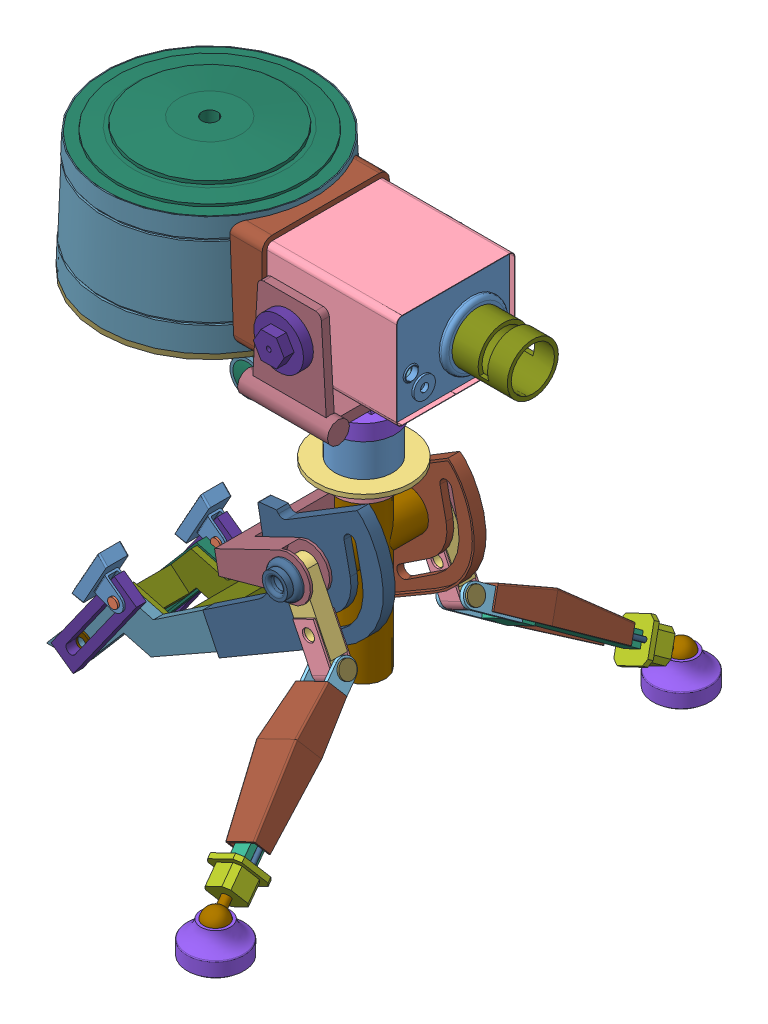
SolidWorks assembly Assem1, configuration AltPosition_Default_1. Lengths in mm.
Overall size (454.66 500.28 528.56).
105 component instances, 64 part files, 136 mates.
Components (placement in the parent):
- center piece assem-2: center piece assem [Default] at (139.2172 608.1262 859.4776) size (134.25 257.4 123.94)
  - center support top section-1: center support top section [Default] at (96.2621 126.254 0) size (58.48 40 58.48)
  - steppo motor-1: steppo motor [Default] at (96.2621 88.254 0) x (0.379391 0 -0.925236) z (-0.925236 0 -0.379391) size (42.44 58.07 42.44)
  - center piece circle wide central ring-1: center piece circle wide central ring [Default] at (96.2621 83.914 0) x (-0.379391 0 0.925236) z (-0.925236 0 -0.379391) size (95 4.34 95)
  - center piece gear support-1: center piece gear support [Default] at (96.2621 51.914 0) x (-0.695714 0 -0.718319) z (0.718319 0 -0.695714) size (55.78 28 55.78)
  - steppo motor screw-1: steppo motor screw [Default] at (87.7742 83.914 -20.287) x (0.961179 0 0.275927) z (0.275927 0 -0.961179) size (5.5 7.62 5.5)
  - steppo motor screw-2: steppo motor screw [Default] at (75.9752 83.914 8.4879) x (0.275927 0 -0.961179) z (-0.961179 0 -0.275927) size (5.5 7.62 5.5)
  - steppo motor screw-3: steppo motor screw [Default] at (104.75 83.914 20.287) x (-0.961179 0 -0.275927) z (-0.275927 0 0.961179) size (5.5 7.62 5.5)
  - steppo motor screw-4: steppo motor screw [Default] at (116.5491 83.914 -8.4879) x (-0.275927 0 0.961179) z (0.961179 0 0.275927) size (5.5 7.62 5.5)
  - center support ball bearign brace-1: center support ball bearign brace [Default] at (96.2621 83.914 0) x (-0.925236 0 -0.379391) z (0.379391 0 -0.925236) size (55.78 10 55.78)
  - center support ball bearign brace top-1: center support ball bearign brace top [Default] at (96.2621 74.914 0) x (-0.922511 0 0.385971) z (-0.385971 0 -0.922511) size (55.78 12 55.78)
  - center piece top hing part-1: center piece top hing part [Default] at (96.2621 123.254 0) x (-1 0 0) z (0 0 -1) size (104.29 49.7 64.01)
  - center support v2-2: center support v2 [Default] at (96.2621 -96.7337 0) size (42.4 158.65 100)
- main side parts-1: main side parts [Default] at (235.4793 627.5876 911.4776) x (0.999891 -0.014742 0) z (0 0 1)
- Mirrormain side parts-2: Mirrormain side parts [Default] at (235.4793 627.5876 807.4776) x (0.999891 -0.014742 0) z (0 0 1)
- wahser spacer-1: wahser spacer [Default] at (235.4793 627.5876 911.4776)
- back handle-1: back handle [Default] at (235.4793 627.5876 924.4776) x (0.986694 0.162587 0) z (0 0 1)
- wahser spacer-2: wahser spacer [Default] at (235.4793 627.5876 935.4776)
- back support-1: back support [Default] at (67.5941 491.4866 904.4776) x (0.999998 0.001848 0) z (0 0 1)
- Mirrorback support-2: Mirrorback support [Default] at (67.5941 491.4866 814.4776) x (0.999998 0.001848 0) z (0 0 1)
- back support backet-1: back support backet [Default] at (28.0399 490.9679 898.4776) x (0.996815 -0.079745 0) z (0 0 1)
- wahser spacer-3: wahser spacer [Default] at (235.4793 627.5876 781.4776)
- wahser spacer-4: wahser spacer [Default] at (235.4793 627.5876 805.4776)
- back foot support bracket-1: back foot support bracket [Default] at (-1.4852 415.687 906.4776) x (0.578557 0.815642 0) z (0 0 1)
- wahser spacer large-1: wahser spacer large [Default] at (-3.7947 436.2499 904.4776) x (0.999256 0.03856 0) z (0 0 1)
- back foot bracket-1: back foot bracket [Default] at (42.2808 501.2065 916.4776) x (-0.48679 -0.873519 0) z (0 0 1)
- back leg pin-1: back leg pin [Default] at (42.2808 501.2065 911.4776)
- back foot support bracket-2: back foot support bracket [Default] at (-1.4852 415.687 802.4776) x (0.578557 0.815642 0) z (0 0 1)
- back foot bracket-2: back foot bracket [Default] at (42.2808 501.2065 812.4776) x (-0.48679 -0.873519 0) z (0 0 1)
- back leg pin-2: back leg pin [Default] at (42.2808 501.2065 807.4776)
- front leg join support-1: front leg join support [Default] at (235.4793 627.5876 915.9776) x (0.900351 0.435164 0) z (0 0 1)
- front leg metal join bracket-1: front leg metal join bracket [Default] at (262.8485 570.5138 924.4776) x (0.900351 0.435164 0) z (0 0 1)
- front leg top half support-1: front leg top half support [Default] at (279.0143 563.4937 924.4776) x (0.900351 0.435164 0) z (-0.355474 0.735472 0.576818)
- front leg top half support-2: front leg top half support [Default] at (258.3063 553.485 924.4776) x (-0.900351 -0.435164 0) z (0.355474 -0.735472 -0.576818)
- front leg midsection suport-1: front leg midsection suport [Default] at (283.5066 527.7725 954.5891) x (0.900351 0.435164 0) z (-0.355474 0.735472 0.576818)
- front leg base support-1: front leg base support [Default] at (311.0558 470.7734 1062.4468) x (0.900351 0.435164 0) z (-0.355474 0.735472 0.576818)
- front foot-1: front foot [Default] at (321.1259 417.8022 1095.0242) x (0.999998 0.001848 0) z (0 0 1)
- front leg ball and socket jont-1: front leg ball and socket jont [Default] at (321.0663 450.0619 1095.0242) x (0.647947 0.717091 0.256798) z (-0.719137 0.464831 0.516502)
- front leg metal join bracket-2: front leg metal join bracket [Default] at (262.8485 570.5138 794.4776) x (0.900351 0.435164 0) z (0 0 1)
- front leg top half support-3: front leg top half support [Default] at (282.6157 565.2344 794.4776) x (-0.900351 -0.435164 0) z (-0.355474 0.735472 -0.576818)
- front leg midsection suport-2: front leg midsection suport [Default] at (276.0416 543.2174 752.253) x (0.900351 0.435164 0) z (0.355474 -0.735472 0.576818)
- front leg base support-2: front leg base support [Default] at (311.0558 470.7734 656.5085) x (0.900351 0.435164 0) z (0.355474 -0.735472 0.576818)
- front leg ball and socket jont-2: front leg ball and socket jont [Default] at (321.0663 450.0619 623.9311) x (0.647947 0.717091 -0.256798) z (0.719137 -0.464831 0.516502)
- front foot-2: front foot [Default] at (321.1259 417.8022 623.9311) x (0.999998 0.001848 0) z (0 0 1)
- front leg join support-3: front leg join support [Default] at (235.4793 627.5876 785.9776) x (0.900351 0.435164 0) z (0 0 1)
- front leg top half support-4: front leg top half support [Default] at (254.7049 551.7443 794.4776) x (0.900351 0.435164 0) z (0.355474 -0.735472 0.576818)
- front foot ligament support-1: front foot ligament support [Default] at (294.5017 533.0242 972.8721) x (-0.960289 -0.027406 0.277656) z (-0.12181 -0.854129 -0.505595)
- front foot ligament support-2: front foot ligament support [Default] at (272.5605 522.4194 972.8721) x (0.748627 0.639123 0.176292) z (-0.613638 0.567282 0.549218)
- front leg metal shroud-1: front leg metal shroud [Default] at (284.766 525.1668 982.9969) x (0.900351 0.435164 0) z (-0.355474 0.735472 0.576818)
- front leg metal shroud-2: front leg metal shroud [Default] at (284.766 525.1668 735.9583) x (-0.900351 -0.435164 0) z (-0.355474 0.735472 -0.576818)
- front foot ligament support-3: front foot ligament support [Default] at (294.5017 533.0242 746.0831) x (-0.960289 -0.027406 -0.277656) z (0.12181 0.854129 -0.505595)
- front foot ligament support-4: front foot ligament support [Default] at (272.5605 522.4194 746.0831) x (0.748627 0.639123 -0.176292) z (0.613638 -0.567282 0.549218)
- frotn foot joing pin-1: frotn foot joing pin [Default] at (282.6157 565.2344 924.4776) x (0.900351 0.435164 0) z (0.119924 -0.248122 0.961277)
- frotn foot joing pin-2: frotn foot joing pin [Default] at (282.6157 565.2344 794.4776) x (0.900351 0.435164 0) z (-0.119924 0.248122 0.961277)
- head bracket-1: head bracket [Default] at (235.4793 770.5 859.4776) x (0 0 -1) z (1 0 0)
- head articulated joint-1: head articulated joint [Default] at (154.1354 726.2042 859.4776) x (-0.360852 0.932623 0) z (0 0 -1)
- head join actuated pin-1: head join actuated pin [Default] at (180.5156 736.4113 859.4776) x (0.923728 0.383049 0) z (-0.383049 0.923728 0)
- head join actuated pin-2: head join actuated pin [Default] at (127.7553 715.9971 859.4776) x (0.833881 0.551944 0) z (0.551944 -0.833881 0)
- head articulated piston femail-1: head articulated piston femail [Default] at (127.7553 715.9971 859.4776) x (0.747 -0.664824 0) z (0 0 1)
- head articulated piston mail-3: head articulated piston mail [Default] at (79.578 758.8746 859.4776) x (0.747 -0.664824 0) z (0 0 1)
- head rectangle ribbing-1: head rectangle ribbing [Default] at (318.4863 844.9499 859.4776) x (-1 0 0) z (0 0 -1)
- head square face-1: head square face [Default] at (318.4863 844.9499 859.4776)
- head rectangle side support-1: head rectangle side support [Default] at (232.1421 846.4499 913.8468)
- Mirrorhead rectangle side support-2: Mirrorhead rectangle side support [Default] at (232.1421 846.4499 805.1085)
- head rectangle ribbing-2: head rectangle ribbing [Default] at (284.9463 844.9499 859.4776) x (-1 0 0) z (0 0 -1)
- head rectangle ribbing-3: head rectangle ribbing [Default] at (251.4063 844.9499 859.4776) x (-1 0 0) z (0 0 -1)
- head rectangle ribbing-4: head rectangle ribbing [Default] at (217.8663 844.9499 859.4776) x (-1 0 0) z (0 0 -1)
- head rectangle ribbing-5: head rectangle ribbing [Default] at (184.3263 844.9499 859.4776) x (-1 0 0) z (0 0 -1)
- head rectangle ribbing-6: head rectangle ribbing [Default] at (150.7863 844.9499 859.4776) x (-1 0 0) z (0 0 -1)
- head square shroud-1: head square shroud [Default] at (328.4863 844.9499 859.4776)
- steppo motor-1: steppo motor [Default] at (171.5619 842.7862 889.6568) x (0.998411 -0.056343 0) z (-0.056343 -0.998411 0) size (42.44 58.07 42.44)
- head motoer holding plate-1: head motoer holding plate [Default] at (227.1363 844.9369 889.6568)
- Arduino UNO-1: Arduino UNO [Default] at (276.2365 843.7288 872.7775) x (1 0 0) z (0 -1 0)
- electronic parts holder small-1: electronic parts holder small [Default] at (318.4863 801.7745 857.862)
- head axle-1: head axle [Default] at (235.4793 838.0632 944.6519)
- electronic parts holder big-1: electronic parts holder big [Default] at (318.4863 801.7745 815.8394)
- motoer clamp-1: motoer clamp [Default] at (171.5619 842.7862 894.6568) x (0.998411 -0.056343 0) z (0 0 1)
- head rectangle buffer piece-1: head rectangle buffer piece [Default] at (197.4352 898.2686 859.9776) size (33.44 106.64 128.74)
- head circuar back base-1: head circuar back base [Default] at (79.578 785.4997 859.4776)
- head base join actuated pin-1: head base join actuated pin [Default] at (79.578 758.8746 859.4776) x (1 0 0) z (0 -1 0) size (28.56 46 28.56)
- head cirular shroud-1: head cirular shroud [Default] at (79.578 785.4997 859.4776) size (219.96 117.43 219.96)
- head circuar top cap-1: head circuar top cap [Default] at (79.578 901.6286 859.4776) size (210.08 14.34 210.08)
- barrle-1: barrle [Default] at (385.375 837.1674 838.4249)
- head decoration bolt-1: head decoration bolt [Default] at (235.4793 838.0632 935.6519) x (0.999787 0.020651 0) z (0 0 1) size (50.28 50.28 20)
- head decoration bolt-2: head decoration bolt [Default] at (235.4793 838.0632 782.6519) x (0.923728 0.383049 0) z (0 0 -1) size (50.28 50.28 20)
- head circuar back rib-1: head circuar back rib [Default] at (82.5478 785.4997 859.6215) x (0.5 0 0.866025) z (-0.866025 0 0.5) size (88.1 119.13 5)
- head circuar back rib-2: head circuar back rib [Default] at (82.078 785.4997 861.0871) x (0 0 1) z (-1 0 0) size (88.1 119.13 5)
- head circuar back rib-3: head circuar back rib [Default] at (80.9383 785.4997 862.1215) x (-0.5 0 0.866025) z (-0.866025 0 -0.5) size (88.1 119.13 5)
- head circuar back rib-4: head circuar back rib [Default] at (79.4341 785.4997 862.4474) x (-0.866025 0 0.5) z (-0.5 0 -0.866025) size (88.1 119.13 5)
- head circuar back rib-5: head circuar back rib [Default] at (77.9685 785.4997 861.9776) x (-1 0 0) z (0 0 -1) size (88.1 119.13 5)
- head circuar back rib-6: head circuar back rib [Default] at (76.9341 785.4997 860.838) x (-0.866025 0 -0.5) z (0.5 0 -0.866025) size (88.1 119.13 5)
- head circuar back rib-7: head circuar back rib [Default] at (76.6082 785.4997 859.3338) x (-0.5 0 -0.866025) z (0.866025 0 -0.5) size (88.1 119.13 5)
- head circuar back rib-8: head circuar back rib [Default] at (77.078 785.4997 857.8681) x (0 0 -1) z (1 0 0) size (88.1 119.13 5)
- head circuar back rib-9: head circuar back rib [Default] at (78.2177 785.4997 856.8338) x (0.5 0 -0.866025) z (0.866025 0 0.5) size (88.1 119.13 5)
- head circuar back top rib support-1: head circuar back top rib support [Default] at (79.578 896.6286 859.4776) x (0.5 0 0.866025) z (-0.866025 0 0.5) size (210.36 5 210.36)
- head circuar back bottom rib support-1: head circuar back bottom rib support [Default] at (79.578 785.4997 859.4776) x (0.5 0 0.866025) z (-0.866025 0 0.5) size (217.96 5 217.96)
- barrle attatchment ring-1: barrle attatchment ring [Default] at (313.4863 837.1674 838.4249) x (0 0 -1) z (1 0 0)
- barrle motor platform-1: barrle motor platform [Default] at (313.4863 861.4112 822.9249) x (0 0 -1) z (-1 0 0)
- barrle motor clip-1: barrle motor clip [Default] at (273.4363 868.452 823.7249) x (1 0 0) z (0 -1 0) size (35.2 29.55 25)
- small barrle motor-1: small barrle motor [Default] at (273.4363 869.452 837.8749) x (1 0 0) z (0 1 0) size (23.5 23.5 38.6)
- barrle motor folower-1: barrle motor folower [Default] at (273.4363 834.6674 837.8749) x (-0.981433 0 0.191806) z (0 1 0) size (18 18 5)
- barrle motor suport-1: barrle motor suport [Default] at (314.8095 837.1674 838.4249) x (0 0 -1) z (1 0 0) size (43.74 16.74 14)
- barrle motor movement pin-1: barrle motor movement pin [Default] at (297.3125 829.6674 837.5266) x (-0.051277 0 0.998684) z (-0.998684 0 -0.051277) size (6.2 5 41.24)
- outter bolt cover-2: outter bolt cover [Default] at (235.4793 627.5876 937.4776) size (35.26 35.26 12)
- outter bolt cover-3: outter bolt cover [Default] at (235.4793 627.5876 781.4776) x (-1 0 0) z (0 0 -1) size (35.26 35.26 12)
Mates (geometry in assembly coordinates):
- Coincident1: coincident anti-aligned: plane of center piece assem-2/center support v2-2 through (235.4793 627.5876 909.4776) normal (0 0 1); circle of main side parts-1
- Concentric4: concentric aligned: circle of main side parts-1; circle of wahser spacer-1
- Coincident3: coincident anti-aligned: plane of main side parts-1 through (306.6597 645.4209 911.4776) normal (0 0 1); plane of wahser spacer-1 through (235.4793 627.5876 911.4776) normal (0 0 -1)
- Coincident5: coincident anti-aligned: circle of back handle-1; cylinder of wahser spacer-2 through (235.4793 627.5876 937.4776) axis (0 0 -1) radius 2.5
- Coincident6: coincident anti-aligned: plane of back handle-1 through (235.4793 627.5876 935.4776) normal (0 0 1); plane of wahser spacer-2 through (235.4793 627.5876 935.4776) normal (0 0 -1)
- Concentric6: concentric aligned: cylinder of wahser spacer-1 through (235.4793 627.5876 913.4776) axis (0 0 -1) radius 2.5; cylinder of back handle-1 through (235.4793 627.5876 935.4776) axis (0 0 -1) radius 2.5
- Coincident8: coincident anti-aligned: plane of wahser spacer-1 through (235.4793 627.5876 913.4776) normal (0 0 1); plane of back handle-1 through (235.4793 627.5876 913.4776) normal (0 0 -1)
- Coincident9: coincident anti-aligned: plane of main side parts-1 through (167.7144 589.8472 904.4776) normal (0 0 -1); plane of back support-1 through (67.5941 491.4866 904.4776) normal (0 0 1)
- Coincident16: coincident anti-aligned: plane of main side parts-1 through (127.0755 531.3307 904.4776) normal (0.556534 -0.830825 0); plane of back support-1 through (67.5941 491.4866 894.4776) normal (-0.556534 0.830825 0)
- Coincident23: coincident anti-aligned: plane of back support-1 through (67.5941 491.4866 898.4776) normal (0 0 -1); plane of back support backet-1 through (28.0399 490.9679 898.4776) normal (0 0 1)
- Coincident24: coincident: point of back support-1; point of back support backet-1
- Coincident26: coincident anti-aligned: line of back support-1 through (67.9591 489.3239 898.4776) axis (0.830825 0.556534 0); line of back support backet-1 through (140.5227 537.9312 898.4776) axis (-0.830825 -0.556534 0)
- Lock1: lock: unknown of main side parts-1; unknown of back support-1
- Concentric7: concentric anti-aligned: cylinder of back support-1 through (-3.7947 436.2499 894.4776) axis (0 0 1) radius 5; cylinder of back foot support bracket-1 through (-3.7947 436.2499 916.4776) axis (0 0 -1) radius 5
- Concentric8: concentric anti-aligned: cylinder of back support-1 through (-3.7947 436.2499 894.4776) axis (0 0 1) radius 5; cylinder of wahser spacer large-1 through (-3.7947 436.2499 906.4776) axis (0 0 -1) radius 5
- Coincident28: coincident anti-aligned: plane of back support-1 through (67.5941 491.4866 904.4776) normal (0 0 1); plane of wahser spacer large-1 through (-3.7947 436.2499 904.4776) normal (0 0 -1)
- Coincident29: coincident anti-aligned: plane of back foot support bracket-1 through (-1.4852 415.687 906.4776) normal (0 0 -1); circle of wahser spacer large-1
- Concentric9: concentric aligned: cylinder of back foot support bracket-1 through (42.2808 501.2065 916.4776) axis (0 0 -1) radius 5; cylinder of back foot bracket-1 through (42.2808 501.2065 918.4776) axis (0 0 -1) radius 5
- Coincident30: coincident anti-aligned: plane of back foot support bracket-1 through (-1.4852 415.687 916.4776) normal (0 0 1); plane of back foot bracket-1 through (42.2808 501.2065 916.4776) normal (0 0 -1)
- Concentric10: concentric aligned: circle of back foot bracket-1; circle of back leg pin-1
- Distance1: distance = 2 mm aligned: plane of back leg pin-1 through (42.2808 501.2065 920.4776) normal (0 0 1); plane of back foot bracket-1 through (42.2808 501.2065 918.4776) normal (0 0 1)
- Concentric11: concentric aligned: circle of back handle-1; circle of front leg join support-1
- Coincident32: coincident anti-aligned: plane of back handle-1 through (235.4793 627.5876 915.9776) normal (0 0 1); plane of front leg join support-1 through (235.4793 627.5876 915.9776) normal (0 0 -1)
- Coincident33: coincident anti-aligned: plane of front leg join support-1 through (235.4793 627.5876 932.9776) normal (0 0 1); plane of front leg metal join bracket-1 through (279.0143 563.4937 932.9776) normal (0 0 -1)
- Concentric12: concentric anti-aligned: cylinder of front leg join support-1 through (254.9797 586.7944 1016.0241) axis (0 0 -1) radius 6.1718; cylinder of front leg metal join bracket-1 through (254.9797 586.7944 913.9776) axis (0 0 1) radius 6.1718
- Parallel1: parallel aligned: line of front leg join support-1 through (275.5367 573.475 932.9776) axis (-0.435164 0.900351 0); line of front leg metal join bracket-1 through (279.0143 563.4937 932.9776) axis (-0.435164 0.900351 0)
- Coincident35: coincident anti-aligned: plane of front leg metal join bracket-1 through (279.0143 563.4937 924.4776) normal (0.900351 0.435164 0); plane of front leg top half support-1 through (279.0143 563.4937 924.4776) normal (-0.900351 -0.435164 0)
- Concentric13: concentric aligned: cylinder of front leg metal join bracket-1 through (279.0143 563.4937 924.4776) axis (-0.900351 -0.435164 0) radius 8.5; cylinder of front leg top half support-1 through (282.6157 565.2344 924.4776) axis (-0.900351 -0.435164 0) radius 8.5
- Concentric14: concentric anti-aligned: cylinder of front leg metal join bracket-1 through (279.0143 563.4937 924.4776) axis (-0.900351 -0.435164 0) radius 8.5; cylinder of front leg top half support-2 through (254.7049 551.7443 924.4776) axis (0.900351 0.435164 0) radius 8.5
- Parallel3: parallel anti-aligned: plane of front leg top half support-1 through (278.8833 572.9569 930.5342) normal (-0.355474 0.735472 0.576818); plane of front leg top half support-2 through (258.4373 544.0218 918.421) normal (0.355474 -0.735472 -0.576818)
- Coincident38: coincident anti-aligned: plane of front leg metal join bracket-1 through (258.3063 553.485 924.4776) normal (-0.900351 -0.435164 0); plane of front leg top half support-2 through (258.3063 553.485 924.4776) normal (0.900351 0.435164 0)
- Coincident42: coincident anti-aligned: plane of front leg top half support-2 through (266.537 527.2638 962.9833) normal (0.251011 -0.519339 0.816873); plane of front leg midsection suport-1 through (212.6877 638.6312 1050.3337) normal (-0.251011 0.519339 -0.816873)
- Coincident44: coincident aligned: plane of front leg top half support-2 through (258.4373 544.0218 918.421) normal (0.355474 -0.735472 -0.576818); plane of front leg midsection suport-1 through (283.5066 527.7725 954.5891) normal (0.355474 -0.735472 -0.576818)
- Coincident45: coincident anti-aligned: plane of front leg top half support-1 through (279.0143 563.4937 924.4776) normal (-0.900351 -0.435164 0); plane of front leg midsection suport-1 through (237.0153 650.3893 1050.3337) normal (0.900351 0.435164 0)
- Coincident46: coincident anti-aligned: plane of front leg midsection suport-1 through (249.2569 578.2986 1149.7972) normal (0.251011 -0.519339 0.816873); plane of front leg base support-1 through (311.0558 470.7734 1062.4468) normal (-0.251011 0.519339 -0.816873)
- Coincident49: coincident anti-aligned: plane of front leg midsection suport-1 through (249.2569 578.2986 1149.7972) normal (-0.900351 -0.435164 0); plane of front leg base support-1 through (311.0854 450.3761 1076.7434) normal (0.900351 0.435164 0)
- Concentric15: concentric: sphere of front foot-1; sphere of front leg ball and socket jont-1
- Concentric16: concentric anti-aligned: cylinder of front leg base support-1 through (313.817 465.0607 1071.4324) axis (0.251011 -0.519339 0.816873) radius 4.3192; cylinder of front leg ball and socket jont-1 through (313.817 465.0607 1071.4324) axis (-0.251011 0.519339 -0.816873) radius 4.3192
- Coincident50: coincident anti-aligned: plane of front leg base support-1 through (313.817 465.0607 1071.4324) normal (0.251011 -0.519339 0.816873); plane of front leg ball and socket jont-1 through (313.817 465.0607 1071.4324) normal (-0.251011 0.519339 -0.816873)
- Concentric17: concentric anti-aligned: circle of front leg midsection suport-1; circle of front foot ligament support-1
- Coincident52: coincident anti-aligned: circle of front leg midsection suport-1; circle of front foot ligament support-1
- Coincident53: coincident anti-aligned: circle of front leg midsection suport-1; circle of front foot ligament support-2
- Coincident54: coincident anti-aligned: line of front leg top half support-2 through (262.8045 534.9862 969.0399) axis (0.900351 0.435164 0); line of front leg metal shroud-1 through (287.114 546.7357 969.0399) axis (-0.900351 -0.435164 0)
- Coincident56: coincident anti-aligned: plane of front leg midsection suport-1 through (295.1005 539.452 976.7747) normal (-0.355474 0.735472 0.576818); plane of front leg base support-1 through (322.2108 468.03 1084.5485) normal (0.355474 -0.735472 -0.576818)
- Coincident57: coincident anti-aligned: line of front leg top half support-2 through (254.5738 561.2074 930.5342) axis (0.251011 -0.519339 0.816873); line of front leg metal shroud-1 through (277.4571 513.8622 1005.004) axis (-0.251011 0.519339 -0.816873)
- Coincident60: coincident aligned: plane of back support-1 through (-3.0718 417.2031 894.4776) normal (0.001848 -0.999998 0); plane of front foot-1 through (321.1259 417.8022 1095.0242) normal (0.001848 -0.999998 0)
- Coincident62: coincident aligned: circle of front leg top half support-1; circle of frotn foot joing pin-1
- Concentric18: concentric aligned: cylinder of center piece assem-2/center piece top hing part-1 through (235.4793 758.9829 848.4776) axis (0 0 1) radius 3.9097; cylinder of head bracket-1 through (235.4793 758.9829 828.4776) axis (0 0 1) radius 4.1675
- Coincident63: coincident anti-aligned: plane of center piece assem-2 through (139.2172 608.1262 859.4776) normal (0 0 1); plane of head bracket-1 through (235.4793 770.5 859.4776) normal (0 0 -1)
- Coincident64: coincident anti-aligned: plane of center piece assem-2/center piece top hing part-1 through (235.4793 731.3801 865.4776) normal (0 0 1); plane of head articulated joint-1 through (154.1354 726.2042 865.4776) normal (0 0 -1)
- Concentric19: concentric aligned: cylinder of center piece assem-2/center piece top hing part-1 through (180.5156 736.4113 853.4776) axis (0 0 1) radius 5.4117; cylinder of head articulated joint-1 through (180.5156 736.4113 851.4776) axis (0 0 1) radius 5.4117
- Coincident65: coincident anti-aligned: plane of head articulated joint-1 through (154.1354 726.2042 851.4776) normal (0 0 -1); plane of head join actuated pin-1 through (180.5156 736.4113 851.4776) normal (0 0 1)
- Coincident66: coincident anti-aligned: plane of head articulated joint-1 through (154.1354 726.2042 851.4776) normal (0 0 -1); plane of head join actuated pin-1 through (180.5156 736.4113 851.4776) normal (0 0 1)
- Concentric20: concentric aligned: cylinder of head articulated joint-1 through (180.5156 736.4113 848.9776) axis (0 0 1) radius 14.2787; cylinder of head join actuated pin-1 through (180.5156 736.4113 848.9776) axis (0 0 1) radius 14.2787
- Coincident67: coincident anti-aligned: plane of head articulated joint-1 through (154.1354 726.2042 851.4776) normal (0 0 -1); plane of head join actuated pin-2 through (127.7553 715.9971 851.4776) normal (0 0 1)
- Concentric21: concentric anti-aligned: cylinder of head articulated joint-1 through (127.7553 715.9971 848.9776) axis (0 0 1) radius 14.2787; cylinder of head join actuated pin-2 through (127.7553 715.9971 869.9776) axis (0 0 -1) radius 14.2787
- Coincident68: coincident anti-aligned: plane of head articulated joint-1 through (154.1354 726.2042 865.4776) normal (0 0 -1); plane of head articulated piston femail-1 through (127.7553 715.9971 865.4776) normal (0 0 1)
- Concentric23: concentric aligned: cylinder of head articulated joint-1 through (127.7553 715.9971 866.9776) axis (0 0 -1) radius 17.3189; cylinder of head articulated piston femail-1 through (127.7553 715.9971 865.4776) axis (0 0 -1) radius 17.3189
- Coincident70: coincident anti-aligned: plane of head articulated piston femail-1 through (118.9731 732.5123 864.9776) normal (-0.664824 -0.747 0); plane of head articulated piston mail-3 through (83.8981 763.7287 864.9776) normal (0.664824 0.747 0)
- Coincident71: coincident anti-aligned: plane of head articulated piston femail-1 through (110.3327 722.804 864.9776) normal (0 0 -1); plane of head articulated piston mail-3 through (79.578 758.8746 864.9776) normal (0 0 1)
- Coincident72: coincident aligned: plane of head rectangle ribbing-1; plane of head square face-1 through (318.4863 844.9499 859.4776) normal (0 1 0)
- Coincident73: coincident anti-aligned: plane of head rectangle ribbing-1 through (318.4863 844.9499 859.4776) normal (0 0 -1); plane of head square face-1 through (318.4863 844.9499 859.4776) normal (0 0 1)
- Concentric24: concentric aligned: cylinder of head bracket-1 through (235.4793 838.0632 934.6519) axis (0 0 -1) radius 2.5; cylinder of head rectangle side support-1 through (235.4793 838.0632 918.8468) axis (0 0 -1) radius 2.5
- Coincident74: coincident aligned: plane of head bracket-1 through (235.4793 770.5 859.4776) normal (0 0 -1); plane of head rectangle ribbing-1 through (318.4863 844.9499 859.4776) normal (0 0 -1)
- Coincident75: coincident anti-aligned: plane of head rectangle ribbing-1 through (313.4863 803.9499 915.3468) normal (0 0 1); plane of head rectangle side support-1 through (318.4863 806.9489 915.3468) normal (0 0 -1)
- Coincident76: coincident anti-aligned: plane of head rectangle ribbing-1 through (313.4863 844.9499 859.4776) normal (-1 0 0); plane of head rectangle side support-1 through (313.4863 806.9489 913.8468) normal (1 0 0)
- Coincident77: coincident anti-aligned: plane of head rectangle ribbing-1 through (313.4863 885.9499 915.3468) normal (0 -1 0); plane of head rectangle side support-1 through (145.798 885.9499 918.8468) normal (0 1 0)
- Coincident78: coincident anti-aligned: plane of head rectangle ribbing-1 through (318.4863 844.9499 859.4776) normal (1 0 0); plane of head square face-1 through (318.4863 844.9499 859.4776) normal (-1 0 0)
- Coincident80: coincident anti-aligned: plane of head rectangle ribbing-1 through (313.4863 892.7686 800.1085) normal (0 1 0); plane of head square shroud-1 through (145.7863 892.7686 913.8468) normal (0 -1 0)
- Coincident81: coincident anti-aligned: plane of head rectangle side support-1 through (232.1421 846.4499 918.8468) normal (0 0 1); plane of head square shroud-1 through (145.7863 802.1313 918.8468) normal (0 0 -1)
- Distance3: distance = 5 mm aligned: plane of head square shroud-1 through (328.4863 802.1313 913.8468) normal (1 0 0); plane of head square face-1 through (323.4863 844.9499 859.4776) normal (1 0 0)
- Coincident83: coincident aligned: plane of head rectangle ribbing-1 through (318.4863 844.9499 859.4776) normal (1 0 0); plane of head motoer holding plate-1 through (318.4863 844.9369 894.6568) normal (1 0 0)
- Coincident84: coincident anti-aligned: plane of head rectangle ribbing-1 through (313.4863 887.0269 889.6568) normal (0 -1 0); plane of head motoer holding plate-1 through (227.1363 887.0269 894.6568) normal (0 1 0)
- Coincident85: coincident anti-aligned: plane of head rectangle ribbing-1 through (313.4863 887.0269 889.6568) normal (0 0 1); plane of head motoer holding plate-1 through (227.1363 844.9369 889.6568) normal (0 0 -1)
- Concentric26: concentric anti-aligned: cylinder of steppo motor-1 through (156.9127 859.1876 885.6568) axis (0 0 1) radius 1.5; cylinder of head motoer holding plate-1 through (156.9127 859.1876 894.6568) axis (0 0 -1) radius 1.5
- Coincident86: coincident anti-aligned: plane of steppo motor-1 through (171.5619 842.7862 889.6568) normal (0 0 1); plane of head motoer holding plate-1 through (227.1363 844.9369 889.6568) normal (0 0 -1)
- Coincident93: coincident aligned: plane of head rectangle ribbing-1 through (318.4863 844.9499 859.4776) normal (1 0 0); plane of electronic parts holder small-1 through (318.4863 801.7745 862.862) normal (1 0 0)
- Coincident96: coincident anti-aligned: plane of head rectangle ribbing-1 through (313.4853 888.1254 859.4776) normal (0 -1 0); plane of electronic parts holder small-1 through (135.7863 888.1254 862.862) normal (0 1 0)
- Coincident97: coincident anti-aligned: plane of head rectangle ribbing-1 through (313.4853 844.9499 857.862) normal (0 0 1); plane of electronic parts holder small-1 through (184.6681 853.6429 857.862) normal (0 0 -1)
- Concentric28: concentric anti-aligned: cylinder of head bracket-1 through (235.4793 838.0632 934.6519) axis (0 0 -1) radius 2.5; cylinder of head axle-1 through (235.4793 838.0632 773.6519) axis (0 0 1) radius 2.5
- Distance6: distance = 10 mm aligned: plane of head axle-1 through (235.4793 838.0632 944.6519) normal (0 0 1); plane of head bracket-1 through (235.4793 770.5 934.6519) normal (0 0 1)
- Coincident102: coincident aligned: plane of head rectangle ribbing-1 through (318.4863 844.9499 859.4776) normal (1 0 0); plane of electronic parts holder big-1 through (318.4863 801.7745 810.8394) normal (1 0 0)
- Coincident103: coincident anti-aligned: plane of electronic parts holder big-1 through (235.6761 836.5729 815.8394) normal (0 0 1); plane of head rectangle ribbing-1 through (313.4853 844.9499 815.8394) normal (0 0 -1)
- Coincident104: coincident anti-aligned: plane of head rectangle ribbing-1 through (313.4853 888.1254 859.4776) normal (0 -1 0); plane of electronic parts holder big-1 through (66.902 888.1254 810.8394) normal (0 1 0)
- Concentric29: concentric anti-aligned: cylinder of steppo motor-1 through (156.9127 859.1876 885.6568) axis (0 0 1) radius 1.5; cylinder of motoer clamp-1 through (156.9127 859.1876 896.6568) axis (0 0 -1) radius 1.5
- Concentric30: concentric anti-aligned: cylinder of steppo motor-1 through (187.9633 857.4353 885.6568) axis (0 0 1) radius 1.5; cylinder of motoer clamp-1 through (187.9633 857.4353 896.6568) axis (0 0 -1) radius 1.5
- Coincident105: coincident anti-aligned: plane of head motoer holding plate-1 through (227.1363 844.9369 894.6568) normal (0 0 1); plane of motoer clamp-1 through (188.5962 858.0006 894.6568) normal (0 0 -1)
- Coincident106: coincident anti-aligned: plane of head square shroud-1 through (145.7863 893.2686 913.8468) normal (0 1 0); plane of head rectangle buffer piece-1 through (197.4352 893.2686 859.9776) normal (0 -1 0)
- Coincident107: coincident anti-aligned: plane of head square shroud-1 through (145.7863 802.1313 919.3468) normal (0 0 1); plane of head rectangle buffer piece-1 through (197.4352 791.6286 919.3468) normal (0 0 -1)
- Distance7: distance = 51.6489 mm anti-aligned: plane of head rectangle buffer piece-1 through (197.4352 791.6286 795.6085) normal (1 0 0); plane of head square shroud-1 through (145.7863 802.1313 913.8468) normal (-1 0 0)
- Coincident109: coincident aligned: plane of center piece assem-2 through (139.2172 608.1262 859.4776) normal (0 0 1); plane of head circuar back base-1 through (79.578 785.4997 859.4776) normal (0 0 1)
- Concentric31: concentric aligned: cylinder of head articulated piston mail-3 through (79.578 758.8746 867.9776) axis (0 0 -1) radius 2.2616; cylinder of head circuar back base-1 through (79.578 758.8746 877.4776) axis (0 0 -1) radius 2.2616
- Coincident110: coincident aligned: plane of head circuar back base-1 through (79.578 785.4997 859.4776) normal (0 0 1); plane of head base join actuated pin-1 through (79.578 758.8746 859.4776) normal (0 0 1)
- Parallel4: parallel anti-aligned: plane of head motoer holding plate-1 through (227.1363 802.8469 894.6568) normal (0 -1 0); plane of head circuar back base-1 through (79.578 785.4997 859.4776) normal (0 1 0)
- Concentric32: concentric anti-aligned: cylinder of head circuar back base-1 through (79.578 758.8746 877.4776) axis (0 0 -1) radius 2.2616; cylinder of head base join actuated pin-1 through (79.578 758.8746 841.4776) axis (0 0 1) radius 2.2616
- Coincident112: coincident aligned: plane of head base join actuated pin-1 through (79.578 758.8746 859.4776) normal (0 0 1); plane of head cirular shroud-1 through (79.578 785.4997 859.4776) normal (0 0 1)
- Coincident113: coincident aligned: plane of head base join actuated pin-1; plane of head cirular shroud-1 through (79.578 785.4997 859.4776) normal (1 0 0)
- Coincident114: coincident anti-aligned: plane of head circuar back base-1 through (79.578 785.4997 859.4776) normal (0 1 0); plane of head cirular shroud-1 through (79.578 785.4997 859.4776) normal (0 -1 0)
- Concentric33: concentric aligned: circle of head cirular shroud-1; cylinder of head circuar top cap-1 through (79.578 913.3046 859.4776) axis (0 1 0) radius 7.9882
- Coincident115: coincident aligned: plane of head cirular shroud-1 through (185.6165 902.929 859.4776) normal (0 1 0); plane of head circuar top cap-1 through (184.616 902.929 859.4776) normal (0 1 0)
- Concentric34: concentric anti-aligned: cylinder of head square face-1 through (329.4863 837.1674 838.4249) axis (-1 0 0) radius 25.869; cylinder of barrle-1 through (309.375 837.1674 838.4249) axis (1 0 0) radius 25.869
- Concentric35: concentric anti-aligned: cylinder of head axle-1 through (235.4793 838.0632 773.6519) axis (0 0 1) radius 2.5; cylinder of head decoration bolt-1 through (235.4793 838.0632 955.6519) axis (0 0 -1) radius 2.5
- Distance9: distance = 1 mm aligned: plane of head axle-1 through (235.4793 838.0632 944.6519) normal (0 0 1); plane of head decoration bolt-1 through (235.4793 838.0632 945.6519) normal (0 0 1)
- Concentric36: concentric aligned: cylinder of head axle-1 through (235.4793 838.0632 773.6519) axis (0 0 1) radius 2.5; cylinder of head decoration bolt-2 through (235.4793 838.0632 762.6519) axis (0 0 1) radius 2.5
- Distance10: distance = 1 mm aligned: plane of head decoration bolt-2 through (235.4793 838.0632 772.6519) normal (0 0 -1); plane of head axle-1 through (235.4793 838.0632 773.6519) normal (0 0 -1)
- Coincident116: coincident anti-aligned: plane of head circuar back base-1 through (81.743 782.4997 858.2276) normal (-0.866025 0 0.5); plane of head circuar back rib-1 through (82.5478 785.4997 859.6215) normal (0.866025 0 -0.5)
- Coincident118: coincident anti-aligned: plane of head circuar back base-1 through (79.578 782.4997 859.4776) normal (0 1 0); plane of head circuar back rib-1 through (78.2177 782.4997 862.1215) normal (0 -1 0)
- Coincident119: coincident anti-aligned: plane of head circuar back rib-1 through (78.2177 896.6286 862.1215) normal (0 1 0); plane of head circuar back top rib support-1 through (79.578 896.6286 859.4776) normal (0 -1 0)
- Concentric38: concentric anti-aligned: circle of head cirular shroud-1; circle of head circuar back top rib support-1
- Coincident121: coincident anti-aligned: plane of head circuar back rib-1 through (82.5478 785.4997 859.6215) normal (0.866025 0 -0.5); plane of head circuar back top rib support-1 through (113.7548 896.6276 913.6736) normal (-0.866025 0 0.5)
- Coincident122: coincident anti-aligned: plane of head circuar back base-1 through (79.578 785.4997 859.4776) normal (0 1 0); plane of head circuar back bottom rib support-1 through (79.578 785.4997 859.4776) normal (0 -1 0)
- Coincident123: coincident anti-aligned: plane of head circuar back rib-1 through (82.5478 785.4997 859.6215) normal (0.866025 0 -0.5); plane of head circuar back bottom rib support-1 through (117.5764 785.4987 920.2929) normal (-0.866025 0 0.5)
- Concentric40: concentric anti-aligned: circle of head circuar back base-1; circle of head circuar back bottom rib support-1
- Coincident125: coincident anti-aligned: plane of head square face-1 through (318.4863 844.9499 859.4776) normal (-1 0 0); plane of barrle attatchment ring-1 through (318.4863 837.1674 838.4249) normal (1 0 0)
- Concentric42: concentric anti-aligned: cylinder of barrle-1 through (309.375 837.1674 838.4249) axis (1 0 0) radius 25.869; cylinder of barrle attatchment ring-1 through (318.4863 837.1674 838.4249) axis (-1 0 0) radius 25.869
- Coincident126: coincident anti-aligned: plane of barrle attatchment ring-1 through (313.4863 837.1674 838.4249) normal (-1 0 0); plane of barrle motor platform-1 through (313.4863 861.4112 817.9249) normal (1 0 0)
- Coincident127: coincident anti-aligned: plane of barrle attatchment ring-1 through (318.4873 863.1632 817.9249) normal (0 1 0); plane of barrle motor platform-1 through (313.4863 863.1632 817.9249) normal (0 -1 0)
- Coincident129: coincident anti-aligned: plane of barrle attatchment ring-1 through (318.4873 869.4361 822.9249) normal (0 0 -1); plane of barrle motor platform-1 through (313.4863 861.4112 822.9249) normal (0 0 1)
- Concentric43: concentric anti-aligned: cylinder of barrle motor platform-1 through (258.4363 846.652 817.9249) axis (0 0 1) radius 1.4; cylinder of barrle motor clip-1 through (258.4363 846.652 852.4786) axis (0 0 -1) radius 1.4
- Concentric44: concentric anti-aligned: cylinder of barrle motor platform-1 through (258.4363 865.652 817.9249) axis (0 0 1) radius 1.4; cylinder of barrle motor clip-1 through (258.4363 865.652 852.4786) axis (0 0 -1) radius 1.4
- Coincident130: coincident anti-aligned: plane of barrle motor platform-1 through (313.4863 861.4112 822.9249) normal (0 0 1); plane of barrle motor clip-1 through (255.8363 843.452 822.9249) normal (0 0 -1)
- Concentric46: concentric aligned: cylinder of barrle motor clip-1 through (273.4363 843.452 837.8749) axis (0 1 0) radius 11.75; cylinder of small barrle motor-1 through (273.4363 845.652 837.8749) axis (0 1 0) radius 11.75
- Distance11: distance = 1 mm aligned: plane of small barrle motor-1 through (273.4363 869.452 837.8749) normal (0 1 0); plane of barrle motor clip-1 through (263.7474 868.452 826.2829) normal (0 1 0)
- Concentric48: concentric anti-aligned: cylinder of small barrle motor-1 through (273.4363 834.152 837.8749) axis (0 1 0) radius 1; cylinder of barrle motor folower-1 through (273.4363 839.6674 837.8749) axis (0 -1 0) radius 2.25
- Concentric49: concentric aligned: cylinder of barrle-1 through (314.8095 837.1674 864.295) axis (0 0 -1) radius 2; cylinder of barrle motor suport-1 through (314.8095 837.1674 820.5559) axis (0 0 -1) radius 2
- Concentric50: concentric anti-aligned: cylinder of barrle-1 through (309.375 837.1674 838.4249) axis (1 0 0) radius 21.869; cylinder of barrle motor suport-1 through (319.8095 837.1674 838.4249) axis (-1 0 0) radius 21.869
- Coincident133: coincident aligned: plane of barrle motor folower-1 through (273.4363 834.6674 837.8749) normal (0 -1 0); plane of barrle motor suport-1 through (321.8095 834.6674 838.4249) normal (0 -1 0)
- Concentric55: concentric aligned: cylinder of barrle motor folower-1 through (279.8156 839.6674 836.6282) axis (0 -1 0) radius 1.1; cylinder of barrle motor movement pin-1 through (279.8156 834.6674 836.6282) axis (0 -1 0) radius 1.1
- Coincident138: coincident anti-aligned: plane of barrle motor folower-1 through (273.4363 834.6674 837.8749) normal (0 -1 0); plane of barrle motor movement pin-1 through (297.3125 834.6674 837.5266) normal (0 1 0)
- Concentric57: concentric anti-aligned: cylinder of barrle motor suport-1 through (314.8095 828.7975 838.4249) axis (0 1 0) radius 1.1; cylinder of barrle motor movement pin-1 through (314.8095 834.6674 838.4249) axis (0 -1 0) radius 1.1
- Coincident144: coincident anti-aligned: plane of head rectangle ribbing-1 through (313.4863 805.7745 881.1802) normal (0 1 0); plane of barrle attatchment ring-1 through (318.4863 805.7745 810.8394) normal (0 -1 0)
- Concentric59: concentric anti-aligned: cylinder of center piece assem-2/center support v2-2 through (235.4793 627.5876 809.4776) axis (0 0 1) radius 20.407; cylinder of main side parts-1 through (235.4793 627.5876 909.4776) axis (0 0 -1) radius 20.407
- Parallel6: parallel aligned: plane of head bracket-1 through (280.9628 775.5 930.6519) normal (1 0 0); plane of head square face-1 through (323.4863 844.9499 859.4776) normal (1 0 0)
- Parallel7: parallel anti-aligned: plane of center piece assem-2/center piece top hing part-1 through (235.4793 747.3801 859.4776) normal (0 1 0); plane of head bracket-1 through (235.4793 770.5 859.4776) normal (0 -1 0)
- Coincident145: coincident anti-aligned: plane of wahser spacer-2 through (235.4793 627.5876 937.4776) normal (0 0 1); plane of outter bolt cover-2 through (235.4793 627.5876 937.4776) normal (0 0 -1)
- Concentric60: concentric aligned: cylinder of back handle-1 through (235.4793 627.5876 935.4776) axis (0 0 -1) radius 21.9693; cylinder of outter bolt cover-2 through (235.4793 627.5876 949.4776) axis (0 0 -1) radius 12.7774
